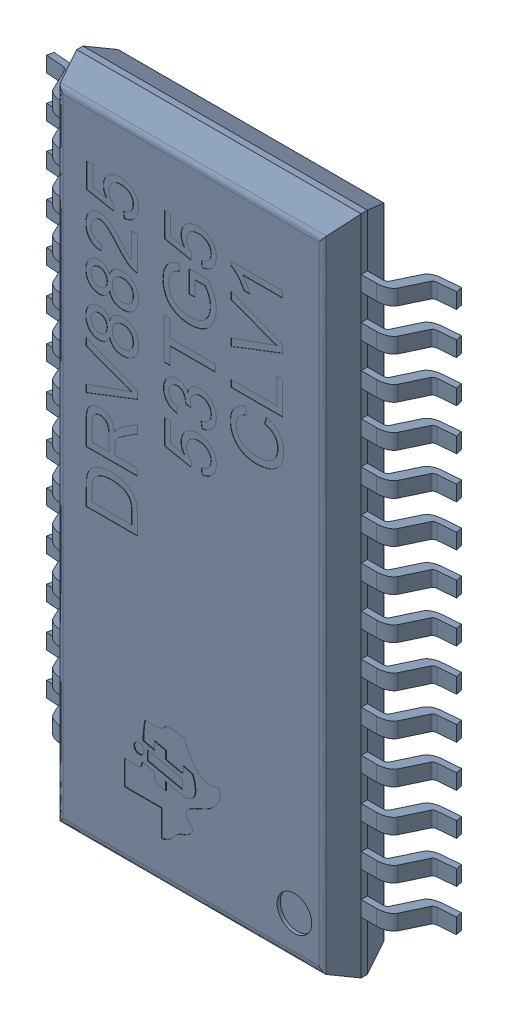
SolidWorks assembly DRV8825 Driver v9 (2), configuration Default. Lengths in mm.
Overall size (6.33 10.21 1.04).
2 component instances, 1 part files, 0 mates.
Components (placement in the parent):
- DRV8825 53TG5 CLV1 (2)-1: DRV8825 53TG5 CLV1 (2) [Default] at (6.5481 7.5317 9.8148) x (1 0 0) z (0 -1 0) size (6.33 1.04 10.21)
  - Package (2)-1: Package (2) [Default] at origin size (6.33 1.04 10.21)
